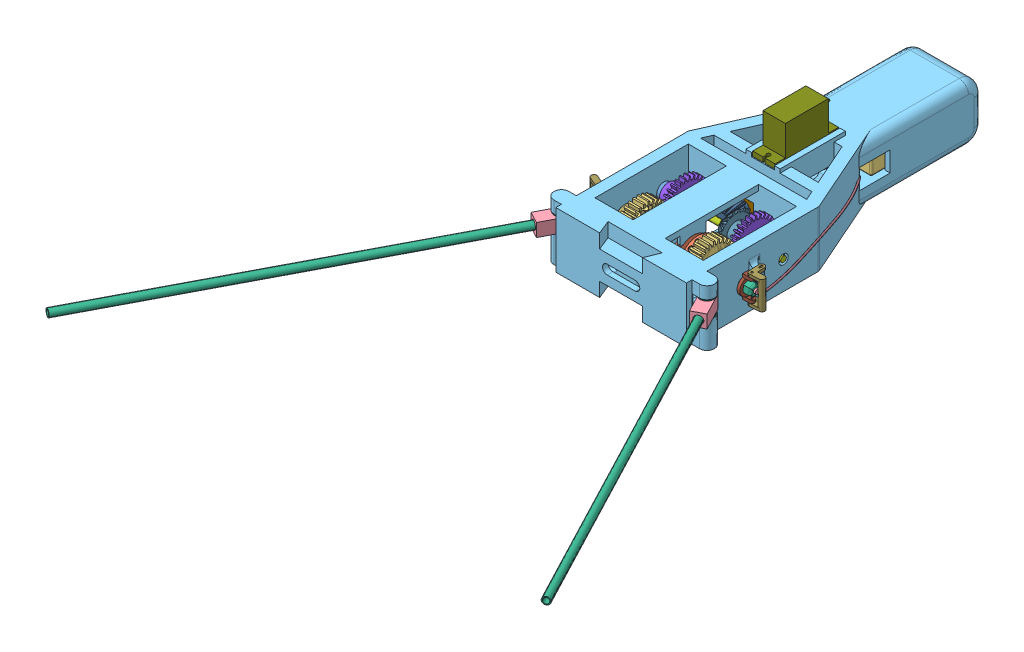
SolidWorks assembly front_assembly, configuration Default. Lengths in mm.
Overall size (271.95 50.4 351.06).
42 component instances, 24 part files, 110 mates.
Components (placement in the parent):
- spool_shaft-1: spool_shaft [Default] at (-1.2695 20.5189 26.3026) size (40 3 3)
- spool_legs-1: spool_legs [Default] at (24.8305 20.5189 26.3026) x (1 0 0) z (0 -0.004493 0.99999) size (7.66 20 20)
- clutch-1: clutch [Default] at (-3.2226 20.5189 26.3026) x (1 0 0) z (0 0.647993 0.761646) size (13.62 24 23.94)
- clutch_shaft-1: clutch_shaft [Default] at (-26.2226 20.5189 26.3026) x (1 0 0) z (0 0.503485 0.864004) size (23 2.4 2.4)
- clutch-2: clutch [Default] at (38.8617 20.5189 26.3026) x (-1 0 0) z (0 -0.014047 0.999901) size (13.62 24 23.94)
- clutch_shaft-2: clutch_shaft [Default] at (38.8617 20.5189 26.3026) x (1 0 0) z (0 -0.459642 0.888105) size (23 2.4 2.4)
- front_body-1: front_body [Default] at (18.7305 5.5189 23.8026) size (86 32 176)
- nylock_nut-1: nylock_nut [Default] at (-21.2226 20.5189 26.3026) x (0 1 0) z (0 0 1) size (6.35 4 5.5)
- nylock_nut-2: nylock_nut [Default] at (56.8617 20.5189 26.3026) x (0 0.381849 -0.924225) z (0 -0.924225 -0.381849) size (6.35 4 5.5)
- drive_shaft-1: drive_shaft [Default] at (-16.2695 20.5189 4.3026) x (1 0 0) z (0 0.127025 -0.9919) size (70 3 3)
- drive_gear-1: drive_gear [Default] at (35.3305 20.5189 4.3026) x (0 -0.531254 0.847213) z (0 0.847213 0.531254) size (23.93 10 24)
- drive_gear-2: drive_gear [Default] at (2.1305 20.5189 4.3026) x (0 0.130916 0.991393) z (0 -0.991393 0.130916) size (23.93 10 24)
- motor-1: motor [Default] at (18.7305 20.5189 -37.6974) x (-1 0 0) z (0 0 1) size (12 10 41.8)
- bevel_gear_motor-2: bevel_gear_motor [Default] at (30.6847 -1.4948 10.226) x (0 -1 0) z (0 0 -1) size (20.12 20.19 11)
- clutch_connector-1: clutch_connector [Default] at (55.3617 20.5189 26.3026) x (0 0 -1) z (0 -1 0) size (9 5 12)
- clutch_link-1: clutch_link [Default] at (58.6965 13.0189 23.808) x (0.997812 0 -0.06611) z (0.06611 0 0.997812) size (8 15 8.5)
- clutch_connector-2: clutch_connector [Default] at (-19.7226 20.5189 26.3026) x (0 0 1) z (0 -1 0) size (9 5 12)
- clutch_link-2: clutch_link [Default] at (-22.2338 28.0189 24.0064) x (-0.918465 0 -0.395503) z (-0.395503 0 0.918465) size (8 15 8.5)
- clutch_wire-1: clutch_wire [Default] at origin size (92.65 1 83.72)
- bevel_gear_shaft-1: bevel_gear_shaft [Default] at (14.207 22.7969 29.2587) x (0 -0.397068 0.917789) z (1 0 0) size (20.11 20.18 14.49)
- bushing-1: bushing [Default] at (12.6305 20.5189 26.3026) x (0 -0.776136 0.630565) z (0 0.630565 0.776136) size (7.5 5 7.5)
- bushing-2: bushing [Default] at (24.8305 20.5189 26.3026) x (0 1 0) z (0 0 1) size (7.5 5 7.5)
- bushing-3: bushing [Default] at (47.7305 20.5189 26.3026) x (0 0.164883 -0.986313) z (0 0.986313 0.164883) size (7.5 5 7.5)
- bushing-4: bushing [Default] at (-10.2695 20.5189 26.3026) x (0 0.975677 0.219213) z (0 0.219213 -0.975677) size (7.5 5 7.5)
- tg9e_micro_servo-1: tg9e_micro_servo [Default] at (18.7305 54.0189 -37.1974) x (0 0 -1) z (-1 0 0) size (34 30 12)
- tg9e_servo_horn_single-1: tg9e_servo_horn_single [Default] at (18.7305 26.5189 -42.6974) x (-0.933998 0 -0.357278) z (-0.357278 0 0.933998) size (7.3 5.6 20.05)
- shaft_spacer-1: shaft_spacer [Default] at (13.6305 20.5189 26.3026) x (1 0 0) z (0 -0.574992 -0.818159) size (2.6 7 7)
- shaft_spacer-2: shaft_spacer [Default] at (21.2305 20.5189 26.3026) size (2.6 7 7)
- bushing_other-1: bushing_other [Default] at (45.8305 20.5189 4.3026) x (0 -0.751627 0.659588) z (0 0.659588 0.751627) size (7.9 5.9 7.9)
- bushing_other-2: bushing_other [Default] at (-8.3695 20.5189 4.3026) x (0 -0.005209 0.999986) z (0 -0.999986 -0.005209) size (7.9 5.9 7.9)
- spool_wings-1: spool_wings [Default] at (12.6305 20.5189 26.3026) x (-1 0 0) z (0 0.999892 -0.014721) size (7.66 20 20)
- battery-1: battery [Default] at (18.7305 20.1189 -119.6974) size (30 10 57)
- shoulder-6: shoulder [Default] at (57.7305 19.2689 49.3026) x (0.886024 0 -0.463639) z (0.463639 0 0.886024) size (7 7 19.5)
- shoulder-7: shoulder [Default] at (-20.2695 19.2689 49.3026) x (0.886024 0 0.463639) z (-0.463639 0 0.886024) size (7 7 19.5)
- solid_rod_3_16mm-1: solid_rod_3_16mm [Default] at (57.7305 15.7689 49.3026) x (0.650489 0 0.759516) z (-0.759516 0 0.650489) size (3 16 3)
- bushing-5: bushing [Default] at (57.7305 20.0189 49.3026) x (0.996468 0 0.083969) z (-0.083969 0 0.996468) size (7.5 5 7.5)
- bushing-6: bushing [Default] at (57.7305 29.0189 49.3026) x (-0.018528 0 -0.999828) z (-0.999828 0 0.018528) size (7.5 5 7.5)
- solid_rod_3_16mm-2: solid_rod_3_16mm [Default] at (-20.2695 15.7689 49.3026) x (-0.934269 0 0.35657) z (-0.35657 0 -0.934269) size (3 16 3)
- bushing-7: bushing [Default] at (-20.2695 29.0189 49.3026) x (-0.018528 0 -0.999828) z (-0.999828 0 0.018528) size (7.5 5 7.5)
- bushing-8: bushing [Default] at (-20.2695 20.0189 49.3026) x (-0.81757 0 -0.575829) z (0.575829 0 -0.81757) size (7.5 5 7.5)
- carbon_rod_4_200mm-1: carbon_rod_4_200mm [Default] at (-22.1241 24.2689 52.8467) x (-0.826526 -0.360269 -0.432505) z (-0.319207 0.932848 -0.167035) size (4 200 4)
- carbon_rod_4_200mm-2: carbon_rod_4_200mm [Default] at (59.585 24.2689 52.8467) x (-0.677567 0.644354 0.354557) z (0.570914 0.764727 -0.298748) size (4 200 4)
Mates (geometry in assembly coordinates):
- Concentric3: concentric aligned: cylinder of spool_shaft-1 through (38.7305 20.5189 26.3026) axis (-1 0 0) radius 1.5; cylinder of clutch-1 through (-3.2226 20.5189 26.3026) axis (-1 0 0) radius 1.4
- Concentric4: concentric aligned: cylinder of clutch-1 through (-3.2226 20.5189 26.3026) axis (-1 0 0) radius 1.4; cylinder of clutch_shaft-1 through (-3.2226 20.5189 26.3026) axis (-1 0 0) radius 1.2
- Distance3: distance = 6 mm anti-aligned: plane of clutch_shaft-1 through (-3.2226 20.5189 26.3026) normal (1 0 0); plane of clutch-1 through (-9.2226 20.5189 26.3026) normal (-1 0 0)
- Concentric5: concentric anti-aligned: cylinder of spool_shaft-1 through (38.7305 20.5189 26.3026) axis (-1 0 0) radius 1.5; cylinder of clutch-2 through (38.8617 20.5189 26.3026) axis (1 0 0) radius 1.4
- Concentric6: concentric anti-aligned: cylinder of clutch-2 through (38.8617 20.5189 26.3026) axis (1 0 0) radius 1.4; cylinder of clutch_shaft-2 through (61.8617 20.5189 26.3026) axis (-1 0 0) radius 1.2
- Distance4: distance = 6 mm anti-aligned: plane of clutch_shaft-2 through (38.8617 20.5189 26.3026) normal (-1 0 0); plane of clutch-2 through (44.8617 20.5189 26.3026) normal (1 0 0)
- Concentric7: concentric anti-aligned: cylinder of clutch_shaft-2 through (61.8617 20.5189 26.3026) axis (-1 0 0) radius 1.2; cylinder of front_body-1 through (-16.2705 20.5189 26.3026) axis (1 0 0) radius 2.45
- Concentric8: concentric anti-aligned: cylinder of clutch_shaft-1 through (-3.2226 20.5189 26.3026) axis (-1 0 0) radius 1.2; cylinder of nylock_nut-1 through (-25.2226 20.5189 26.3026) axis (1 0 0) radius 1.2
- Distance6: distance = 1 mm aligned: plane of clutch_shaft-1 through (-26.2226 20.5189 26.3026) normal (-1 0 0); plane of nylock_nut-1 through (-25.2226 20.5189 26.3026) normal (-1 0 0)
- Concentric10: concentric aligned: cylinder of clutch_shaft-2 through (61.8617 20.5189 26.3026) axis (-1 0 0) radius 1.2; cylinder of nylock_nut-2 through (60.8617 20.5189 26.3026) axis (-1 0 0) radius 1.2
- Distance7: distance = 1 mm aligned: plane of clutch_shaft-2 through (61.8617 20.5189 26.3026) normal (1 0 0); plane of nylock_nut-2 through (60.8617 20.5189 26.3026) normal (1 0 0)
- Distance8: distance = 9 mm anti-aligned: plane of front_body-1 through (47.7305 35.5189 -8.6974) normal (-1 0 0); plane of spool_shaft-1 through (38.7305 20.5189 26.3026) normal (1 0 0)
- Parallel1: parallel aligned: plane of front_body-1 through (18.7305 35.5189 23.8026) normal (0 1 0); plane of assembly through (0 0 0) normal (0 1 0)
- Distance10: distance = 22.9 mm aligned: plane of spool_legs-1 through (24.8305 20.5189 26.3026) normal (-1 0 0); plane of front_body-1 through (47.7305 35.5189 -8.6974) normal (-1 0 0)
- Concentric12: concentric anti-aligned: cylinder of front_body-1 through (-16.2705 20.5189 4.3026) axis (1 0 0) radius 2.55; cylinder of drive_shaft-1 through (53.7305 20.5189 4.3026) axis (-1 0 0) radius 1.5
- Coincident17: coincident aligned: plane of front_body-1 through (53.7305 35.5189 -14.6974) normal (1 0 0); plane of drive_shaft-1 through (53.7305 20.5189 4.3026) normal (1 0 0)
- Concentric13: concentric aligned: cylinder of drive_shaft-1 through (53.7305 20.5189 4.3026) axis (-1 0 0) radius 1.5; cylinder of drive_gear-2 through (2.1305 20.5189 4.3026) axis (-1 0 0) radius 1.8
- Concentric14: concentric anti-aligned: cylinder of drive_shaft-1 through (53.7305 20.5189 4.3026) axis (-1 0 0) radius 1.5; cylinder of drive_gear-1 through (35.3305 20.5189 4.3026) axis (1 0 0) radius 1.8
- Distance11: distance = 9.4 mm anti-aligned: plane of front_body-1 through (47.7305 35.5189 -8.6974) normal (-1 0 0); plane of drive_gear-1 through (38.3305 20.5189 4.3026) normal (1 0 0)
- Distance12: distance = 9.4 mm anti-aligned: plane of front_body-1 through (-10.2695 35.5189 -8.6974) normal (1 0 0); plane of drive_gear-2 through (-0.8695 20.5189 4.3026) normal (-1 0 0)
- Coincident130: coincident anti-aligned: plane of front_body-1 through (24.7305 25.5189 62.3036) normal (0 -1 0); plane of motor-1 through (22.1805 25.5189 -22.6974) normal (0 1 0)
- Coincident131: coincident anti-aligned: plane of front_body-1 through (24.7305 25.5189 62.3036) normal (-1 0 0); plane of motor-1 through (24.7305 15.5189 -10.0974) normal (1 0 0)
- Concentric17: concentric aligned: cylinder of clutch_shaft-2 through (61.8617 20.5189 26.3026) axis (-1 0 0) radius 1.2; cylinder of clutch_connector-1 through (56.8617 20.5189 26.3026) axis (-1 0 0) radius 1.7
- Coincident40: coincident anti-aligned: plane of nylock_nut-2 through (56.8617 20.5189 26.3026) normal (-1 0 0); plane of clutch_connector-1 through (56.8617 20.5189 26.3026) normal (1 0 0)
- Parallel2: parallel aligned: plane of front_body-1 through (18.7305 35.5189 23.8026) normal (0 1 0); plane of clutch_connector-1 through (60.3617 26.5189 27.8026) normal (0 1 0)
- Concentric18: concentric aligned: cylinder of clutch_connector-1 through (58.8617 26.5189 26.3026) axis (0 -1 0) radius 0.5; cylinder of clutch_link-1 through (58.8617 28.0189 26.3026) axis (0 -1 0) radius 0.5
- Coincident42: coincident anti-aligned: plane of clutch_connector-1 through (60.3617 26.5189 27.8026) normal (0 1 0); plane of clutch_link-1 through (63.8508 26.5189 25.972) normal (0 -1 0)
- Tangent1: tangent anti-aligned: cylinder of front_body-1 through (58.5305 5.5188 21.3026) axis (0 1 0) radius 0.5; plane of clutch_link-1 through (57.9992 28.0189 20.8476) normal (0.997812 0 -0.06611)
- Concentric19: concentric anti-aligned: cylinder of clutch_shaft-1 through (-3.2226 20.5189 26.3026) axis (-1 0 0) radius 1.2; cylinder of clutch_connector-2 through (-21.2226 20.5189 26.3026) axis (1 0 0) radius 1.7
- Coincident43: coincident anti-aligned: plane of nylock_nut-1 through (-21.2226 20.5189 26.3026) normal (1 0 0); plane of clutch_connector-2 through (-21.2226 20.5189 26.3026) normal (-1 0 0)
- Parallel3: parallel anti-aligned: plane of front_body-1 through (18.7305 35.5189 23.8026) normal (0 1 0); plane of clutch_connector-2 through (-24.7226 14.5189 24.8026) normal (0 -1 0)
- Concentric20: concentric anti-aligned: cylinder of clutch_connector-2 through (-23.2226 26.5189 26.3026) axis (0 -1 0) radius 0.5; cylinder of clutch_link-2 through (-23.2226 26.5189 26.3026) axis (0 1 0) radius 0.5
- Coincident45: coincident anti-aligned: plane of clutch_connector-2 through (-24.7226 14.5189 24.8026) normal (0 -1 0); plane of clutch_link-2 through (-27.8149 14.5189 24.325) normal (0 1 0)
- Tangent2: tangent anti-aligned: cylinder of front_body-1 through (-21.0695 5.5188 21.3026) axis (0 1 0) radius 0.5; plane of clutch_link-2 through (-20.5881 26.5189 21.4488) normal (-0.918465 0 -0.395503)
- Concentric32: concentric aligned: cylinder of ? through (41.7305 29.5189 49.3026) axis (0 -1 0) radius 1.5; cylinder of ? through (41.7305 35.5189 49.3026) axis (0 -1 0) radius 1.5
- Concentric33: concentric anti-aligned: cylinder of front_body-1 through (41.7305 5.5188 49.3026) axis (0 1 0) radius 2.45; cylinder of ? through (41.7305 35.5189 49.3026) axis (0 -1 0) radius 1.5
- Tangent5: tangent anti-aligned: plane of front_body-1 through (500018.7305 29.5189 56.3026) normal (0 -1 0); face of ?
- Concentric34: concentric anti-aligned: cylinder of ? through (51.7295 24.5189 49.4415) axis (-0.999903 0 -0.013893) radius 2; cylinder of ? through (44.7302 24.5189 49.3442) axis (0.999903 0 0.013893) radius 2
- Tangent6: tangent anti-aligned: cylinder of ? through (41.7305 29.5189 49.3026) axis (0 -1 0) radius 3; plane of ? through (44.7302 24.5189 49.3442) normal (-0.999903 0 -0.013893)
- LimitDistance3: limit distance = 1.6313 mm anti-aligned: plane of front_body-1 through (53.7305 35.5189 -14.6974) normal (1 0 0); plane of clutch_connector-1 through (55.3617 20.5189 26.3026) normal (-1 0 0)
- LimitDistance4: limit distance = 3.4531 mm anti-aligned: plane of front_body-1 through (-16.2695 35.5189 -14.6974) normal (-1 0 0); plane of clutch_connector-2 through (-19.7226 20.5189 26.3026) normal (1 0 0)
- LimitDistance5: limit distance = 2.0313 mm anti-aligned: plane of spool_legs-1 through (30.8305 20.5189 26.3026) normal (1 0 0); plane of clutch-2 through (32.8617 20.5189 26.3026) normal (-1 0 0)
- LimitDistance7: limit distance = 4.4439 mm: cylinder of front_body-1 through (-21.0695 5.5188 21.3026) axis (0 1 0) radius 0.5; cylinder of clutch_connector-2 through (-23.2226 26.5189 26.3026) axis (0 -1 0) radius 0.5
- LimitDistance8: limit distance = 4.011 mm: cylinder of front_body-1 through (58.5305 5.5188 21.3026) axis (0 1 0) radius 0.5; cylinder of clutch_connector-1 through (58.8617 26.5189 26.3026) axis (0 -1 0) radius 0.5
- Concentric37: concentric anti-aligned: cylinder of drive_shaft-1 through (53.7305 20.5189 4.3026) axis (-1 0 0) radius 1.5; cylinder of bevel_gear_shaft-1 through (28.3305 20.5189 4.3026) axis (1 0 0) radius 1.8
- Coincident122: coincident anti-aligned: plane of drive_gear-1 through (35.3305 20.5189 4.3026) normal (-1 0 0); plane of bevel_gear_shaft-1 through (35.3305 20.5189 4.3026) normal (1 0 0)
- Distance23: distance = 1 mm anti-aligned: plane of motor-1 through (18.7305 20.5189 -1.3974) normal (0 0 1); plane of bevel_gear_motor-2 through (18.7305 20.5415 -0.3974) normal (0 0 -1)
- Distance27: distance = 0.3 mm anti-aligned: plane of motor-1 through (17.7305 19.4009 -1.3974) normal (-1 0 0); plane of bevel_gear_motor-2 through (17.4305 21.637 -3.8974) normal (1 0 0)
- Concentric45: concentric aligned: cylinder of spool_shaft-1 through (38.7305 20.5189 26.3026) axis (-1 0 0) radius 1.5; cylinder of bushing-1 through (13.3805 20.5189 26.3026) axis (-1 0 0) radius 1.5
- Concentric47: concentric anti-aligned: cylinder of spool_shaft-1 through (38.7305 20.5189 26.3026) axis (-1 0 0) radius 1.5; cylinder of bushing-2 through (24.0805 20.5189 26.3026) axis (1 0 0) radius 1.5
- Concentric48: concentric anti-aligned: cylinder of spool_legs-1 through (24.8305 20.5189 26.3026) axis (1 0 0) radius 2.45; cylinder of bushing-2 through (29.0805 20.5189 26.3026) axis (-1 0 0) radius 2.25
- Coincident66: coincident anti-aligned: plane of spool_legs-1 through (24.8305 20.5189 26.3026) normal (-1 0 0); plane of bushing-2 through (24.8305 20.5189 26.3026) normal (1 0 0)
- Coincident67: coincident anti-aligned: plane of front_body-1 through (47.7305 35.5189 -8.6974) normal (-1 0 0); plane of bushing-3 through (47.7305 20.5189 26.3026) normal (1 0 0)
- Concentric49: concentric anti-aligned: cylinder of clutch_shaft-2 through (61.8617 20.5189 26.3026) axis (-1 0 0) radius 1.2; cylinder of bushing-3 through (46.9805 20.5189 26.3026) axis (1 0 0) radius 1.5
- Coincident68: coincident anti-aligned: plane of front_body-1 through (-10.2695 35.5189 -8.6974) normal (1 0 0); plane of bushing-4 through (-10.2695 20.5189 26.3026) normal (-1 0 0)
- Concentric50: concentric aligned: cylinder of clutch_shaft-1 through (-3.2226 20.5189 26.3026) axis (-1 0 0) radius 1.2; cylinder of bushing-4 through (-9.5195 20.5189 26.3026) axis (-1 0 0) radius 1.5
- Concentric54: concentric aligned: cylinder of tg9e_micro_servo-1 through (18.7305 24.0189 -42.6974) axis (0 1 0) radius 2.5; cylinder of tg9e_servo_horn_single-1 through (18.7305 22.5189 -42.6974) axis (0 1 0) radius 2.5
- Coincident77: coincident anti-aligned: plane of front_body-1 through (18.7305 35.5189 23.8026) normal (0 1 0); plane of tg9e_micro_servo-1 through (24.7305 35.5189 -20.1974) normal (0 -1 0)
- Coincident80: coincident anti-aligned: plane of front_body-1 through (16.2305 -499994.4811 33.3026) normal (-1 0 0); plane of shaft_spacer-1 through (16.2305 20.5189 26.3026) normal (1 0 0)
- Concentric55: concentric aligned: cylinder of spool_shaft-1 through (38.7305 20.5189 26.3026) axis (-1 0 0) radius 1.5; cylinder of shaft_spacer-1 through (16.2305 20.5189 26.3026) axis (-1 0 0) radius 1.6
- Coincident81: coincident anti-aligned: plane of front_body-1 through (21.2305 -499994.4811 33.3026) normal (1 0 0); plane of shaft_spacer-2 through (21.2305 20.5189 26.3026) normal (-1 0 0)
- Concentric56: concentric aligned: cylinder of spool_shaft-1 through (38.7305 20.5189 26.3026) axis (-1 0 0) radius 1.5; cylinder of shaft_spacer-2 through (23.8305 20.5189 26.3026) axis (-1 0 0) radius 1.6
- Concentric57: concentric aligned: cylinder of drive_shaft-1 through (53.7305 20.5189 4.3026) axis (-1 0 0) radius 1.5; cylinder of bushing_other-1 through (47.7305 20.5189 4.3026) axis (-1 0 0) radius 1.6
- Coincident82: coincident anti-aligned: plane of front_body-1 through (47.7305 35.5189 -8.6974) normal (-1 0 0); plane of bushing_other-1 through (47.7305 20.5189 4.3026) normal (1 0 0)
- Concentric58: concentric anti-aligned: cylinder of drive_shaft-1 through (53.7305 20.5189 4.3026) axis (-1 0 0) radius 1.5; cylinder of bushing_other-2 through (-10.2695 20.5189 4.3026) axis (1 0 0) radius 1.6
- Coincident84: coincident anti-aligned: plane of front_body-1 through (-10.2695 35.5189 -8.6974) normal (1 0 0); plane of bushing_other-2 through (-10.2695 20.5189 4.3026) normal (-1 0 0)
- Concentric59: concentric anti-aligned: cylinder of front_body-1 through (18.7305 5.5178 -22.6974) axis (0 1 0) radius 0.8; cylinder of tg9e_micro_servo-1 through (18.7305 40.5189 -22.6974) axis (0 -1 0) radius 1
- Concentric60: concentric anti-aligned: cylinder of front_body-1 through (18.7305 5.5178 -51.6974) axis (0 1 0) radius 0.8; cylinder of tg9e_micro_servo-1 through (18.7305 40.5189 -51.6974) axis (0 -1 0) radius 1
- Concentric61: concentric anti-aligned: cylinder of bushing-1 through (8.3805 20.5189 26.3026) axis (1 0 0) radius 2.25; cylinder of spool_wings-1 through (12.6305 20.5189 26.3026) axis (-1 0 0) radius 2.45
- Coincident89: coincident anti-aligned: plane of bushing-1 through (12.6305 20.5189 26.3026) normal (-1 0 0); plane of spool_wings-1 through (12.6305 20.5189 26.3026) normal (1 0 0)
- Distance25: distance = 22.9 mm aligned: plane of front_body-1 through (-10.2695 35.5189 -8.6974) normal (1 0 0); plane of spool_wings-1 through (12.6305 20.5189 26.3026) normal (1 0 0)
- LimitDistance9: limit distance = 3.8531 mm: plane of clutch-1 through (2.7774 20.5189 26.3026) normal (1 0 0); point of spool_wings-1
- Coincident90: coincident anti-aligned: plane of front_body-1 through (18.4805 20.5189 -37.6974) normal (0 0 1); plane of motor-1 through (18.9074 20.5189 -37.6974) normal (0 0 -1)
- Distance26: distance = 0.5 mm anti-aligned: plane of tg9e_servo_horn_single-1 through (18.7305 26.5189 -42.6974) normal (0 1 0); plane of tg9e_micro_servo-1 through (18.7305 27.0189 -39.6974) normal (0 -1 0)
- Coincident92: coincident anti-aligned: plane of front_body-1 through (36.8727 15.1189 -119.6974) normal (0 1 0); plane of battery-1 through (3.7305 15.1189 -62.6974) normal (0 -1 0)
- Coincident93: coincident aligned: plane of front_body-1 through (18.7305 5.5189 -119.6974) normal (0 0 -1); plane of battery-1 through (18.7305 20.1189 -119.6974) normal (0 0 -1)
- Concentric65: concentric anti-aligned: cylinder of shoulder-6 through (57.7305 20.7679 49.3026) axis (0 1 0) radius 1.8; cylinder of solid_rod_3_16mm-1 through (57.7305 31.7689 49.3026) axis (0 -1 0) radius 1.5
- Concentric67: concentric aligned: cylinder of front_body-1 through (57.7305 15.5189 49.3026) axis (0 1 0) radius 2.45; cylinder of bushing-5 through (57.7305 15.7689 49.3026) axis (0 1 0) radius 2.25
- Coincident103: coincident anti-aligned: plane of front_body-1 through (53.7305 20.0189 33.261) normal (0 1 0); plane of bushing-5 through (57.7305 20.0189 49.3026) normal (0 -1 0)
- Coincident105: coincident aligned: plane of solid_rod_3_16mm-1 through (57.7305 15.7689 49.3026) normal (0 -1 0); plane of bushing-5 through (57.7305 15.7689 49.3026) normal (0 -1 0)
- Concentric68: concentric aligned: cylinder of solid_rod_3_16mm-1 through (57.7305 31.7689 49.3026) axis (0 -1 0) radius 1.5; cylinder of bushing-5 through (57.7305 20.7689 49.3026) axis (0 -1 0) radius 1.5
- Concentric69: concentric aligned: cylinder of front_body-1 through (57.7305 33.5189 49.3026) axis (0 -1 0) radius 2.45; cylinder of bushing-6 through (57.7305 33.2689 49.3026) axis (0 -1 0) radius 2.25
- Coincident107: coincident anti-aligned: plane of front_body-1 through (53.7305 29.0189 33.261) normal (0 -1 0); plane of bushing-6 through (57.7305 29.0189 49.3026) normal (0 1 0)
- Coincident108: coincident anti-aligned: plane of shoulder-6 through (56.8906 20.7689 40.1486) normal (0 -1 0); plane of bushing-5 through (57.7305 20.7689 49.3026) normal (0 1 0)
- Concentric70: concentric anti-aligned: cylinder of shoulder-7 through (-20.2695 20.7679 49.3026) axis (0 1 0) radius 1.8; cylinder of solid_rod_3_16mm-2 through (-20.2695 31.7689 49.3026) axis (0 -1 0) radius 1.5
- Concentric71: concentric anti-aligned: cylinder of ? through (-31.283 20.0189 52.1667) axis (0 1 0) radius 1.6; cylinder of solid_rod_3_16mm-2 through (-31.283 32.0189 52.1667) axis (0 -1 0) radius 1.5
- Concentric72: concentric aligned: cylinder of ? through (-31.283 29.0189 52.1667) axis (0 -1 0) radius 1.6; cylinder of solid_rod_3_16mm-2 through (-31.283 32.0189 52.1667) axis (0 -1 0) radius 1.5
- Coincident109: coincident anti-aligned: plane of front_body-1 through (-16.2695 29.0189 33.261) normal (0 -1 0); plane of ? through (-31.283 29.0189 52.1667) normal (0 1 0)
- Coincident110: coincident aligned: plane of ? through (-31.283 16.0189 52.1667) normal (0 -1 0); plane of solid_rod_3_16mm-2 through (-31.283 16.0189 52.1667) normal (0 -1 0)
- Coincident111: coincident anti-aligned: plane of ? through (-31.283 21.9189 52.1667) normal (0 1 0); plane of shoulder-7 through (-27.783 21.9189 43.6667) normal (0 -1 0)
- Coincident112: coincident anti-aligned: plane of front_body-1 through (-16.2695 20.0189 33.261) normal (0 1 0); plane of ? through (-31.283 20.0189 52.1667) normal (0 -1 0)
- Concentric73: concentric aligned: cylinder of solid_rod_3_16mm-2 through (-20.2695 31.7689 49.3026) axis (0 -1 0) radius 1.5; cylinder of bushing-8 through (-20.2695 20.7689 49.3026) axis (0 -1 0) radius 1.5
- Coincident113: coincident anti-aligned: plane of shoulder-7 through (-13.2275 20.7689 43.3941) normal (0 -1 0); plane of bushing-8 through (-20.2695 20.7689 49.3026) normal (0 1 0)
- Coincident114: coincident anti-aligned: plane of front_body-1 through (-16.2695 20.0189 33.261) normal (0 1 0); plane of bushing-8 through (-20.2695 20.0189 49.3026) normal (0 -1 0)
- Coincident115: coincident anti-aligned: plane of front_body-1 through (-16.2695 29.0189 33.261) normal (0 -1 0); plane of bushing-7 through (-20.2695 29.0189 49.3026) normal (0 1 0)
- Concentric74: concentric anti-aligned: cylinder of solid_rod_3_16mm-2 through (-20.2695 31.7689 49.3026) axis (0 -1 0) radius 1.5; cylinder of bushing-7 through (-20.2695 28.2689 49.3026) axis (0 1 0) radius 1.5
- Coincident116: coincident aligned: plane of solid_rod_3_16mm-2 through (-20.2695 15.7689 49.3026) normal (0 -1 0); plane of bushing-8 through (-20.2695 15.7689 49.3026) normal (0 -1 0)
- Concentric76: concentric aligned: cylinder of front_body-1 through (-20.2695 15.5189 49.3026) axis (0 1 0) radius 2.45; cylinder of bushing-8 through (-20.2695 15.7689 49.3026) axis (0 1 0) radius 2.25
- Concentric77: concentric anti-aligned: cylinder of shoulder-7 through (-22.1241 24.2689 52.8467) axis (-0.463639 0 0.886024) radius 2.2; cylinder of carbon_rod_4_200mm-1 through (-114.8519 24.2689 230.0515) axis (0.463639 0 -0.886024) radius 2
- Coincident117: coincident anti-aligned: plane of shoulder-7 through (-22.1241 24.2689 52.8467) normal (-0.463639 0 0.886024); plane of carbon_rod_4_200mm-1 through (-22.1241 24.2689 52.8467) normal (0.463639 0 -0.886024)
- Concentric78: concentric anti-aligned: cylinder of shoulder-6 through (59.585 24.2689 52.8467) axis (0.463639 0 0.886024) radius 2.2; cylinder of carbon_rod_4_200mm-2 through (152.3128 24.2689 230.0515) axis (-0.463639 0 -0.886024) radius 2
- Coincident118: coincident anti-aligned: plane of shoulder-6 through (59.585 24.2689 52.8467) normal (0.463639 0 0.886024); plane of carbon_rod_4_200mm-2 through (59.585 24.2689 52.8467) normal (-0.463639 0 -0.886024)
- Symmetric1: symmetric aligned: plane of shoulder-6 through (54.6294 19.2689 50.9253) normal (-0.886024 0 0.463639); plane of shoulder-7 through (-17.1685 19.2689 50.9253) normal (0.886024 0 0.463639); plane of assembly through (18.7305 0 0) normal (1 0 0)
- Distance29: distance = 1.044 mm: point of motor-1; point of bevel_gear_motor-2
- Distance30: distance = 0.3 mm anti-aligned: plane of battery-1 through (3.7305 25.1189 -62.6974) normal (-1 0 0); plane of front_body-1 through (3.4305 500005.5189 -119.6974) normal (1 0 0)
- Concentric83: concentric aligned: cylinder of front_body-1 through (26.2305 17.5189 -54.6984) axis (0 0 1) radius 2.55; cylinder of ? through (26.2305 17.5189 62.3026) axis (0 0 1) radius 2.25
- Concentric84: concentric aligned: cylinder of front_body-1 through (11.2305 14.5189 -54.6984) axis (0 0 1) radius 2.55; cylinder of ? through (11.2305 14.5189 56.3026) axis (0 0 1) radius 2.45
- Concentric85: concentric aligned: cylinder of front_body-1 through (26.2305 16.5189 -54.6984) axis (0 0 1) radius 2.55; cylinder of ? through (26.2305 16.5189 56.3026) axis (0 0 1) radius 2.45
- Coincident128: coincident anti-aligned: plane of front_body-1 through (26.2305 16.5189 60.3026) normal (0 0 1); plane of ? through (26.2305 16.5189 60.3026) normal (0 0 -1)
- Coincident129: coincident aligned: plane of ? through (26.2305 16.5189 62.2026) normal (0 0 1); plane of ? through (11.2305 14.5189 62.2026) normal (0 0 1)
